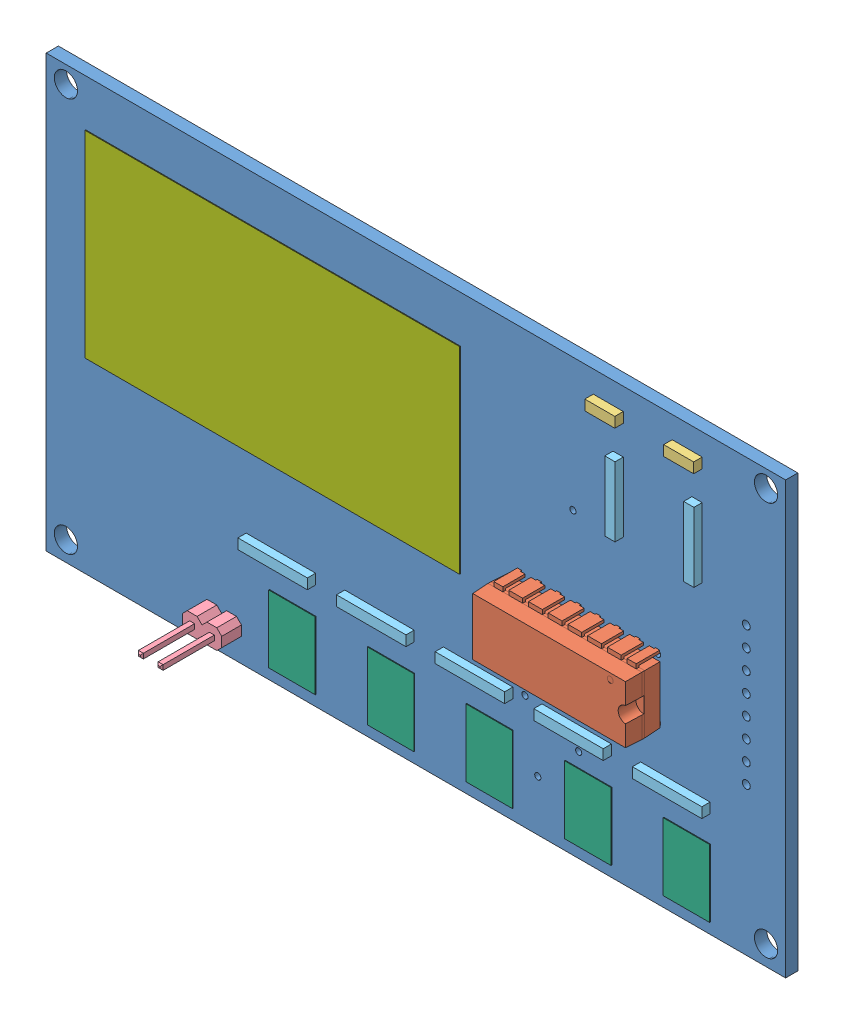
SolidWorks assembly PCB, configuration Default. Lengths in mm.
Overall size (95.23 55.55 12.97).
19 component instances, 7 part files, 0 mates.
Components (placement in the parent):
- PCB Component-1: PCB Component [Default] at origin size (95.23 55.55 12.97)
  - Board-1: Board [Default] at origin size (95.23 55.55 1.57)
  - 4532N-1: 4532N [Default] at (74.93 115.57 1.57) x (-1 0 0) z (0 0 1) size (19.81 8.66 8.71)
  - LED3MM-1: LED3MM [Default] at (87.63 143.51 1.57) size (3.86 1.32 1.09)
  - LED3MM-2: LED3MM [Default] at (77.47 143.51 1.57) size (3.86 1.32 1.09)
  - 1X02-1: 1X02 [Default] at (27.686 95.123 1.57) size (5.08 2.54 12.64)
  - 510-1: 510 [Default] at (35.306 105.664 1.57) x (-1 0 0) z (0 0 1) size (8.94 1.32 1.06)
  - 510-2: 510 [Default] at (48.006 105.664 1.57) x (-1 0 0) z (0 0 1) size (8.94 1.32 1.06)
  - 510-3: 510 [Default] at (60.706 105.664 1.57) x (-1 0 0) z (0 0 1) size (8.94 1.32 1.06)
  - 510-4: 510 [Default] at (73.406 105.664 1.57) x (-1 0 0) z (0 0 1) size (8.94 1.32 1.06)
  - 510-5: 510 [Default] at (86.106 105.537 1.57) x (-1 0 0) z (0 0 1) size (8.94 1.32 1.06)
  - 510-6: 510 [Default] at (88.9 134.62 1.57) x (0 -1 0) z (0 0 1) size (8.94 1.32 1.06)
  - 510-7: 510 [Default] at (78.74 134.62 1.57) x (0 -1 0) z (0 0 1) size (8.94 1.32 1.06)
  - FSM8JH-1: FSM8JH [Default] at (36.83 97.79 1.57) x (0 1 0) z (0 0 1) size (8.7 6 0.1)
  - FSM8JH-2: FSM8JH [Default] at (49.53 97.79 1.57) x (0 1 0) z (0 0 1) size (8.7 6 0.1)
  - FSM8JH-3: FSM8JH [Default] at (62.23 97.79 1.57) x (0 1 0) z (0 0 1) size (8.7 6 0.1)
  - FSM8JH-4: FSM8JH [Default] at (74.93 97.79 1.57) x (0 1 0) z (0 0 1) size (8.7 6 0.1)
  - FSM8JH-5: FSM8JH [Default] at (87.63 97.79 1.57) x (0 1 0) z (0 0 1) size (8.7 6 0.1)
  - ESP12E_DEVKIT-1: ESP12E_DEVKIT [Default] at (34.29 128.27 1.57) x (0 1 0) z (0 0 1) size (25.4 48.26 0.1)
